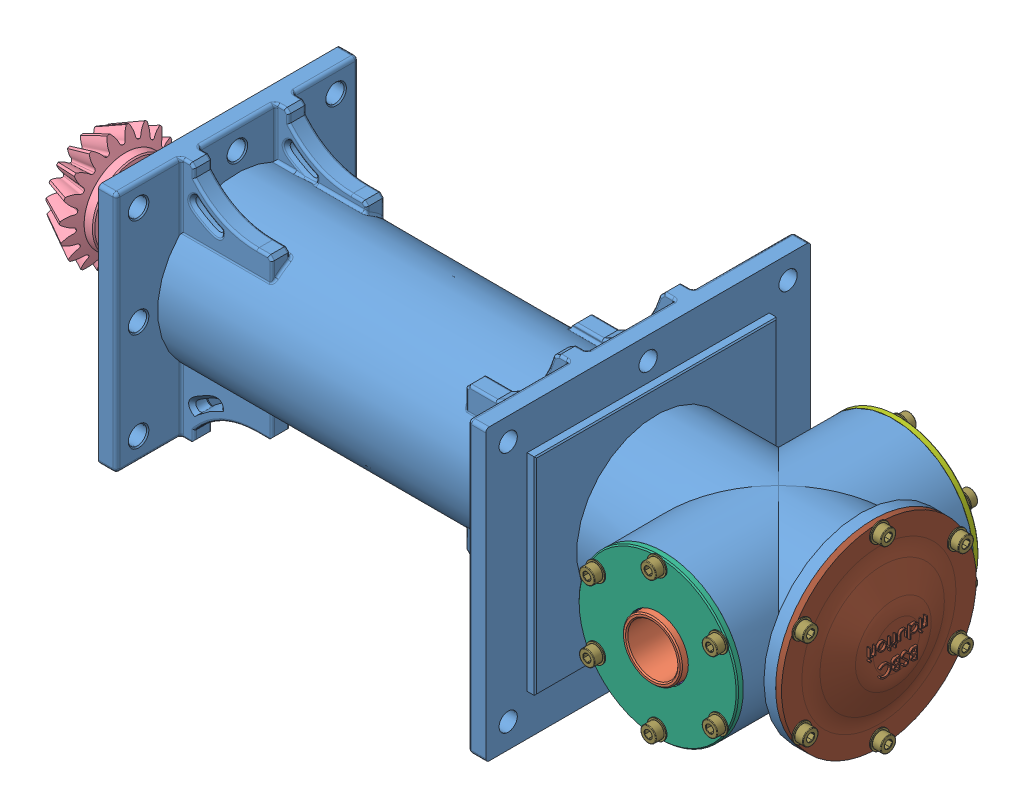
SolidWorks assembly assieme_input, configuration Default. Lengths in mm.
80 component instances, 22 part files, 63 mates.
Components (placement in the parent):
- carter input-1: carter input [Default] at (125.1796 -12.4449 563.34) size (563.34 245.5 275)
- input_ok-1: input_ok [Default] at (125.1796 -12.4449 670.74) x (0 0 1) z (0.402129 -0.915583 0) size (214.8 54.7 54.7)
- SKF_6210-1: SKF_6210 [Default] at (125.1796 -12.4449 476.84) x (0 0 1) z (0.402129 -0.915583 0) size (20 90 90)
  - SKF_6210_14-1: SKF_6210_14 [Default] x (1 0 0) z (0 -0.587785 0.809017) size (12.7 12.7 12.7)
  - SKF_6210_14-2: SKF_6210_14 [Default] x (1 0 0) z (0 -0.951057 0.309017) size (12.7 12.7 12.7)
  - SKF_6210_14-3: SKF_6210_14 [Default] x (1 0 0) z (0 -0.951057 -0.309017) size (12.7 12.7 12.7)
  - SKF_6210_14-4: SKF_6210_14 [Default] x (1 0 0) z (0 -0.587785 -0.809017) size (12.7 12.7 12.7)
  - SKF_6210_14-5: SKF_6210_14 [Default] x (1 0 0) z (0 0 -1) size (12.7 12.7 12.7)
  - SKF_6210_14-6: SKF_6210_14 [Default] x (1 0 0) z (0 0.587785 -0.809017) size (12.7 12.7 12.7)
  - SKF_6210_14-7: SKF_6210_14 [Default] x (1 0 0) z (0 0.951057 -0.309017) size (12.7 12.7 12.7)
  - SKF_6210_14-8: SKF_6210_14 [Default] x (1 0 0) z (0 0.951057 0.309017) size (12.7 12.7 12.7)
  - SKF_6210_14-9: SKF_6210_14 [Default] x (1 0 0) z (0 0.587785 0.809017) size (12.7 12.7 12.7)
  - SKF_6210_14-10: SKF_6210_14 [Default] at origin size (12.7 12.7 12.7)
  - SKF_6210_25-1: SKF_6210_25 [Default] at origin size (20 90 90)
  - SKF_6210_27-1: SKF_6210_27 [Default] at origin size (20 62.51 62.51)
- SKF_6210-2: SKF_6210 [Default] at (125.1796 -12.4449 629.84) x (0 0 1) z (0.402129 -0.915583 0) size (20 90 90)
  - SKF_6210_14-1: SKF_6210_14 [Default] x (1 0 0) z (0 -0.587785 0.809017) size (12.7 12.7 12.7)
  - SKF_6210_14-2: SKF_6210_14 [Default] x (1 0 0) z (0 -0.951057 0.309017) size (12.7 12.7 12.7)
  - SKF_6210_14-3: SKF_6210_14 [Default] x (1 0 0) z (0 -0.951057 -0.309017) size (12.7 12.7 12.7)
  - SKF_6210_14-4: SKF_6210_14 [Default] x (1 0 0) z (0 -0.587785 -0.809017) size (12.7 12.7 12.7)
  - SKF_6210_14-5: SKF_6210_14 [Default] x (1 0 0) z (0 0 -1) size (12.7 12.7 12.7)
  - SKF_6210_14-6: SKF_6210_14 [Default] x (1 0 0) z (0 0.587785 -0.809017) size (12.7 12.7 12.7)
  - SKF_6210_14-7: SKF_6210_14 [Default] x (1 0 0) z (0 0.951057 -0.309017) size (12.7 12.7 12.7)
  - SKF_6210_14-8: SKF_6210_14 [Default] x (1 0 0) z (0 0.951057 0.309017) size (12.7 12.7 12.7)
  - SKF_6210_14-9: SKF_6210_14 [Default] x (1 0 0) z (0 0.587785 0.809017) size (12.7 12.7 12.7)
  - SKF_6210_14-10: SKF_6210_14 [Default] at origin size (12.7 12.7 12.7)
  - SKF_6210_25-1: SKF_6210_25 [Default] at origin size (20 90 90)
  - SKF_6210_27-1: SKF_6210_27 [Default] at origin size (20 62.51 62.51)
- coperchio.n2-1: coperchio.n2 [Default] at (125.1796 -12.4449 665.74) x (-1 0 0) z (0 0 -1) size (135 135 15.9)
- coperchio.n3-1: coperchio.n3 [Default] at (125.1796 -12.4449 460.94) size (135 135 11)
- tenuta 0.1 e 0.2 e 6-1: tenuta 0.1 e 0.2 e 6 [Default] at (125.1796 -12.4449 463.94) x (0 0 1) z (-1 0 0) size (8 70 70)
- tenuta 0.1 e 0.2 e 6-2: tenuta 0.1 e 0.2 e 6 [Default] at (125.1796 -12.4449 662.74) x (0 0 -1) z (1 0 0) size (8 70 70)
- anello_uni_7436-55-1: anello_uni_7436-55 [Default] at (124.7248 -12.5816 584.84) x (-0.903159 -0.429307 0) z (0 0 1) size (57.38 64.07 3)
- anello_uni_7436-50-4: anello_uni_7436-50 [Default] at (124.7295 -12.5699 473.84) x (-0.915583 -0.402129 0) z (0 0 1) size (52.25 60.43 3)
- anello_uni_7436-50-6: anello_uni_7436-50 [Default] at (125.5762 -12.198 649.84) x (-0.915583 -0.402129 0) z (0 0 1) size (52.25 60.43 3)
- coperchio..n1-1: coperchio..n1 [Default] at (220.1796 -12.4449 563.34) x (1 0 0) z (0 0 -1) size (27 165 165)
- SOLID bulloni a brugola M8 coperchi vari-13: SOLID bulloni a brugola M8 coperchi vari [Default] at (125.1796 -72.4449 476.94) x (-1 0 0) z (0 0 -1) size (16 16 24.35)
- SOLID bulloni a brugola M8 coperchi vari-14: SOLID bulloni a brugola M8 coperchi vari [Default] at (73.2181 -42.4449 476.94) x (-0.5 0.866025 0) z (0 0 -1) size (16 16 24.35)
- SOLID bulloni a brugola M8 coperchi vari-15: SOLID bulloni a brugola M8 coperchi vari [Default] at (73.2181 17.5551 476.94) x (0.5 0.866025 0) z (0 0 -1) size (16 16 24.35)
- SOLID bulloni a brugola M8 coperchi vari-16: SOLID bulloni a brugola M8 coperchi vari [Default] at (125.1796 47.5551 476.94) x (1 0 0) z (0 0 -1) size (16 16 24.35)
- SOLID bulloni a brugola M8 coperchi vari-17: SOLID bulloni a brugola M8 coperchi vari [Default] at (177.1411 17.5551 476.94) x (0.5 -0.866025 0) z (0 0 -1) size (16 16 24.35)
- SOLID bulloni a brugola M8 coperchi vari-18: SOLID bulloni a brugola M8 coperchi vari [Default] at (177.1411 -42.4449 476.94) x (-0.5 -0.866025 0) z (0 0 -1) size (16 16 24.35)
- SOLID bulloni a brugola M8 coperchi vari-19: SOLID bulloni a brugola M8 coperchi vari [Default] at (125.1796 -72.4449 649.74) x (-0.820736 0.571308 0) z (0 0 1) size (16 16 24.35)
- SOLID bulloni a brugola M8 coperchi vari-20: SOLID bulloni a brugola M8 coperchi vari [Default] at (177.1411 -42.4449 649.74) x (-0.905135 -0.425124 0) z (0 0 1) size (16 16 24.35)
- SOLID bulloni a brugola M8 coperchi vari-21: SOLID bulloni a brugola M8 coperchi vari [Default] at (177.1411 17.5551 649.74) x (-0.0844 -0.996432 0) z (0 0 1) size (16 16 24.35)
- SOLID bulloni a brugola M8 coperchi vari-22: SOLID bulloni a brugola M8 coperchi vari [Default] at (125.1796 47.5551 649.74) x (0.820736 -0.571308 0) z (0 0 1) size (16 16 24.35)
- SOLID bulloni a brugola M8 coperchi vari-23: SOLID bulloni a brugola M8 coperchi vari [Default] at (73.2181 17.5551 649.74) x (0.905135 0.425124 0) z (0 0 1) size (16 16 24.35)
- SOLID bulloni a brugola M8 coperchi vari-24: SOLID bulloni a brugola M8 coperchi vari [Default] at (73.2181 -42.4449 649.74) x (0.0844 0.996432 0) z (0 0 1) size (16 16 24.35)
- SOLID bulloni a brugola M8 coperchi vari-25: SOLID bulloni a brugola M8 coperchi vari [Default] at (194.1796 -88.4449 563.34) x (0 0.000788 -1) z (1 0 0) size (16 16 24.35)
- SOLID bulloni a brugola M8 coperchi vari-26: SOLID bulloni a brugola M8 coperchi vari [Default] at (194.1796 -50.4449 629.1579) x (0 -0.865631 -0.500683) z (1 0 0) size (16 16 24.35)
- SOLID bulloni a brugola M8 coperchi vari-27: SOLID bulloni a brugola M8 coperchi vari [Default] at (194.1796 25.5551 629.1579) x (0 -0.866419 0.499317) z (1 0 0) size (16 16 24.35)
- SOLID bulloni a brugola M8 coperchi vari-28: SOLID bulloni a brugola M8 coperchi vari [Default] at (194.1796 63.5551 563.34) x (0 -0.000788 1) z (1 0 0) size (16 16 24.35)
- SOLID bulloni a brugola M8 coperchi vari-29: SOLID bulloni a brugola M8 coperchi vari [Default] at (194.1796 25.5551 497.5221) x (0 0.865631 0.500683) z (1 0 0) size (16 16 24.35)
- SOLID bulloni a brugola M8 coperchi vari-30: SOLID bulloni a brugola M8 coperchi vari [Default] at (194.1796 -50.4449 497.5221) x (0 0.866419 -0.499317) z (1 0 0) size (16 16 24.35)
- SKF_NUP_208_ECJ-2: SKF_NUP_208_ECJ [Default] at (19.4696 -12.4449 563.34) x (1 0 0) z (0 -0.998638 -0.052166) size (18 80 80)
  - SKF_NUP_208_ECJ_3-1: SKF_NUP_208_ECJ_3 [Default] x (1 0 0) z (0 -0.433884 0.900969) size (11 11 11)
  - SKF_NUP_208_ECJ_3-2: SKF_NUP_208_ECJ_3 [Default] x (1 0 0) z (0 -0.781831 0.62349) size (11 11 11)
  - SKF_NUP_208_ECJ_3-3: SKF_NUP_208_ECJ_3 [Default] x (1 0 0) z (0 -0.974928 0.222521) size (11 11 11)
  - SKF_NUP_208_ECJ_3-4: SKF_NUP_208_ECJ_3 [Default] x (1 0 0) z (0 -0.974928 -0.222521) size (11 11 11)
  - SKF_NUP_208_ECJ_3-5: SKF_NUP_208_ECJ_3 [Default] x (1 0 0) z (0 -0.781831 -0.62349) size (11 11 11)
  - SKF_NUP_208_ECJ_3-6: SKF_NUP_208_ECJ_3 [Default] x (1 0 0) z (0 -0.433884 -0.900969) size (11 11 11)
  - SKF_NUP_208_ECJ_3-7: SKF_NUP_208_ECJ_3 [Default] x (1 0 0) z (0 0 -1) size (11 11 11)
  - SKF_NUP_208_ECJ_3-8: SKF_NUP_208_ECJ_3 [Default] x (1 0 0) z (0 0.433884 -0.900969) size (11 11 11)
  - SKF_NUP_208_ECJ_3-9: SKF_NUP_208_ECJ_3 [Default] x (1 0 0) z (0 0.781831 -0.62349) size (11 11 11)
  - SKF_NUP_208_ECJ_3-10: SKF_NUP_208_ECJ_3 [Default] x (1 0 0) z (0 0.974928 -0.222521) size (11 11 11)
  - SKF_NUP_208_ECJ_3-11: SKF_NUP_208_ECJ_3 [Default] x (1 0 0) z (0 0.974928 0.222521) size (11 11 11)
  - SKF_NUP_208_ECJ_3-12: SKF_NUP_208_ECJ_3 [Default] x (1 0 0) z (0 0.781831 0.62349) size (11 11 11)
  - SKF_NUP_208_ECJ_3-13: SKF_NUP_208_ECJ_3 [Default] x (1 0 0) z (0 0.433884 0.900969) size (11 11 11)
  - SKF_NUP_208_ECJ_3-14: SKF_NUP_208_ECJ_3 [Default] at origin size (11 11 11)
  - SKF_NUP_208_ECJ_20-1: SKF_NUP_208_ECJ_20 [Default] at origin size (18 80 80)
  - SKF_NUP_208_ECJ_22-1: SKF_NUP_208_ECJ_22 [Default] at origin size (18 54 54)
- SOLID ruota 1-1: SOLID ruota 1 [Default] at (129.3382 -12.4449 563.34) x (0 -0.179924 -0.983681) z (-1 0 0) size (103.91 103.86 54.88)
- RUOTA0_OK-1: RUOTA0_OK [Default] at (125.1796 -12.4449 559.8714) x (-0.995036 -0.099517 0) z (0 0 1) size (105.59 105.67 33.5)
- anello_o40-uni_7435-4: anello_o40-uni_7435 [Default] at (86.9716 -12.4449 563.34) x (0 0.947589 0.319493) z (1 0 0) size (41.38 47.49 1.75)
- SOLID albero 2-2: SOLID albero 2 [Default] at (92.4716 -12.4449 563.34) x (0 -0.619232 -0.785208) z (-1 0 0) size (40 40 555)
- OR 1-1: OR 1 [Default] at (203.6796 -12.4449 563.34) x (0 0 -1) z (1 0 0) size (140 140 3)
- OR 2-1: OR 2 [Default] at (125.1796 -12.4449 464.44) x (0.998746 0.05006 0) z (0 0 1) size (105 105 3)
- OR 2-2: OR 2 [Default] at (125.1796 -12.4449 659.24) size (105 105 3)
- SOLID ruota 2-1: SOLID ruota 2 [Default] at (-528.6431 -12.4449 563.34) x (0 0.329379 0.944198) z (1 0 0) size (100.08 99.94 103.04)
- anello_o40-uni_7435-5: anello_o40-uni_7435 [Default] at (-456.2784 -12.4449 563.34) x (0 0.681304 -0.732001) z (1 0 0) size (41.38 47.49 1.75)
Mates (geometry in assembly coordinates):
- Concentrico2: concentric anti-aligned: cylinder of input_ok-1 through (125.1796 -12.4449 670.74) axis (0 0 -1) radius 25; cylinder of SKF_6210-1/SKF_6210_27-1 through (125.1796 -12.4449 576.84) axis (0 0 1) radius 25
- Concentrico3: concentric anti-aligned: cylinder of input_ok-1 through (125.1796 -12.4449 670.74) axis (0 0 -1) radius 25; cylinder of SKF_6210-2/SKF_6210_27-1 through (125.1796 -12.4449 729.84) axis (0 0 1) radius 25
- Coincidente1: coincident anti-aligned: plane of input_ok-1 through (100.1384 -23.4431 629.84) normal (0 0 1); plane of SKF_6210-2/SKF_6210_27-1 through (96.8987 -24.866 629.84) normal (0 0 -1)
- Coincidente2: coincident anti-aligned: plane of input_ok-1 through (102.29 -22.4981 496.84) normal (0 0 -1); plane of SKF_6210-1/SKF_6210_27-1 through (101.2829 -22.9404 496.84) normal (0 0 1)
- Concentrico6: concentric aligned: cylinder of carter input-1 through (125.1796 -12.4449 629.84) axis (0 0 1) radius 45; cylinder of SKF_6210-2/SKF_6210_25-1 through (125.1796 -12.4449 679.84) axis (0 0 1) radius 45
- Coincidente7: coincident anti-aligned: plane of carter input-1 through (125.1796 -12.4449 629.84) normal (0 0 1); plane of SKF_6210-2/SKF_6210_25-1 through (84.9855 -30.0983 629.84) normal (0 0 -1)
- Concentrico7: concentric anti-aligned: cylinder of coperchio.n2-1 through (125.1796 -12.4449 654.74) axis (0 0 1) radius 35; cylinder of tenuta 0.1 e 0.2 e 6-2 through (125.1796 -12.4449 612.74) axis (0 0 -1) radius 35
- Coincidente8: coincident anti-aligned: plane of coperchio.n2-1 through (125.1796 -12.4449 662.74) normal (0 0 -1); plane of tenuta 0.1 e 0.2 e 6-2 through (125.1796 21.5551 662.74) normal (0 0 1)
- Concentrico8: concentric aligned: cylinder of coperchio.n3-1 through (125.1796 -12.4449 463.94) axis (0 0 1) radius 35; cylinder of tenuta 0.1 e 0.2 e 6-1 through (125.1796 -12.4449 513.94) axis (0 0 1) radius 35
- Coincidente10: coincident anti-aligned: plane of coperchio.n3-1 through (125.1796 -12.4449 463.94) normal (0 0 1); plane of tenuta 0.1 e 0.2 e 6-1 through (125.1796 21.5551 463.94) normal (0 0 -1)
- Concentrico9: concentric aligned: circle of carter input-1; circle of coperchio.n3-1
- Coincidente11: coincident anti-aligned: plane of carter input-1 through (125.1796 -12.4449 465.94) normal (0 0 -1); plane of coperchio.n3-1 through (125.1796 -12.4449 465.94) normal (0 0 1)
- Concentrico10: concentric aligned: cylinder of carter input-1 through (125.1796 -12.4449 629.84) axis (0 0 1) radius 45; cylinder of coperchio.n2-1 through (125.1796 -12.4449 654.74) axis (0 0 1) radius 45
- Coincidente17: coincident anti-aligned: plane of carter input-1 through (125.1796 -12.4449 660.74) normal (0 0 1); plane of coperchio.n2-1 through (125.1796 -12.4449 660.74) normal (0 0 -1)
- Concentrico11: concentric aligned: cylinder of carter input-1 through (125.1796 -72.4449 660.74) axis (0 0 1) radius 3.4; cylinder of coperchio.n2-1 through (125.1796 -72.4449 665.74) axis (0 0 1) radius 4.5
- Concentrico14: concentric anti-aligned: cylinder of input_ok-1 through (125.1796 -12.4449 670.74) axis (0 0 -1) radius 25; cylinder of anello_uni_7436-55-1 through (125.1796 -12.4449 587.84) axis (0 0 1) radius 29.157
- Coincidente21: coincident: point of input_ok-1; line of anello_uni_7436-55-1 through (106.325 19.1391 584.84) axis (0.429307 -0.903159 0)
- Concentrico15: concentric anti-aligned: cylinder of input_ok-1 through (125.1796 -12.4449 670.74) axis (0 0 -1) radius 25; cylinder of anello_uni_7436-50-4 through (125.1796 -12.4449 476.84) axis (0 0 1) radius 26.5875
- Coincidente22: coincident anti-aligned: plane of input_ok-1 through (125.1796 -12.4449 476.84) normal (0 0 -1); plane of anello_uni_7436-50-4 through (136.1796 -4.9971 476.84) normal (0 0 1)
- Perpendicolare1: perpendicular: plane of input_ok-1 through (108.3332 -0.0751 520.94) normal (0.402129 -0.915583 0); line of anello_uni_7436-50-4 through (118.1035 9.9767 473.84) axis (-0.402129 0.915583 0)
- Concentrico17: concentric aligned: cylinder of input_ok-1 through (125.1796 -12.4449 670.74) axis (0 0 -1) radius 25; cylinder of anello_uni_7436-50-6 through (125.1796 -12.4449 649.84) axis (0 0 -1) radius 26.5875
- Perpendicolare2: perpendicular: plane of input_ok-1 through (127.4689 8.3294 583.94) normal (0.402129 -0.915583 0); plane of anello_uni_7436-50-6 through (120.2803 7.3201 651.34) normal (-0.915583 -0.402129 0)
- Coincidente26: coincident anti-aligned: plane of carter input-1 through (205.1796 -12.4449 563.34) normal (1 0 0); plane of coperchio..n1-1 through (205.1796 -69.9449 563.34) normal (-1 0 0)
- Concentrico18: concentric aligned: cylinder of carter input-1 through (205.1796 -12.4449 563.34) axis (-1 0 0) radius 82.5; cylinder of coperchio..n1-1 through (210.1796 -12.4449 563.34) axis (-1 0 0) radius 82.5
- Concentrico19: concentric anti-aligned: cone of carter input-1 through (205.1796 -88.4449 563.34) axis (-1 0 0); cylinder of coperchio..n1-1 through (210.1796 -88.4449 563.34) axis (1 0 0) radius 4.25
- Concentrico20: concentric anti-aligned: cylinder of carter input-1 through (125.1796 -72.4449 465.94) axis (0 0 -1) radius 3.4; cylinder of SOLID bulloni a brugola M8 coperchi vari-13 through (125.1796 -72.4449 460.94) axis (0 0 1) radius 4
- Vite1: screw = 1 anti-aligned: cylinder of carter input-1 through (125.1796 -72.4449 465.94) axis (0 0 -1) radius 3.4; cylinder of SOLID bulloni a brugola M8 coperchi vari-13 through (125.1796 -72.4449 460.94) axis (0 0 1) radius 4
- Coincidente27: coincident anti-aligned: plane of coperchio.n3-1 through (125.1796 -12.4449 460.94) normal (0 0 -1); plane of SOLID bulloni a brugola M8 coperchi vari-13 through (125.1796 -72.4449 460.94) normal (0 0 1)
- Coincidente28: coincident anti-aligned: plane of input_ok-1 through (125.1796 -12.4449 649.84) normal (0 0 1); plane of anello_uni_7436-50-6 through (137.0263 -4.6252 649.84) normal (0 0 -1)
- Perpendicolare3: perpendicular: plane of input_ok-1 through (127.4689 8.3294 583.94) normal (0.402129 -0.915583 0); plane of anello_uni_7436-50-6 through (120.2803 7.3201 651.34) normal (-0.915583 -0.402129 0)
- Concentrico22: concentric anti-aligned: cylinder of carter input-1 through (125.1796 -72.4449 660.74) axis (0 0 1) radius 3.4; cylinder of SOLID bulloni a brugola M8 coperchi vari-19 through (125.1796 -72.4449 665.74) axis (0 0 -1) radius 4
- Vite2: screw = 1 anti-aligned: cylinder of carter input-1 through (125.1796 -72.4449 660.74) axis (0 0 1) radius 3.4; cylinder of SOLID bulloni a brugola M8 coperchi vari-19 through (125.1796 -72.4449 665.74) axis (0 0 -1) radius 4
- Coincidente31: coincident anti-aligned: plane of coperchio.n2-1 through (125.1796 -12.4449 665.74) normal (0 0 1); plane of SOLID bulloni a brugola M8 coperchi vari-19 through (125.1796 -72.4449 665.74) normal (0 0 -1)
- Concentrico24: concentric anti-aligned: cylinder of carter input-1 through (205.1796 -88.4449 563.34) axis (1 0 0) radius 3.4; cylinder of SOLID bulloni a brugola M8 coperchi vari-25 through (210.1796 -88.4449 563.34) axis (-1 0 0) radius 4
- Vite3: screw = 1 anti-aligned: cylinder of carter input-1 through (205.1796 -88.4449 563.34) axis (1 0 0) radius 3.4; cylinder of SOLID bulloni a brugola M8 coperchi vari-25 through (210.1796 -88.4449 563.34) axis (-1 0 0) radius 4
- Coincidente32: coincident anti-aligned: plane of coperchio..n1-1 through (210.1796 -71.0431 563.34) normal (1 0 0); plane of SOLID bulloni a brugola M8 coperchi vari-25 through (210.1796 -88.4449 563.34) normal (-1 0 0)
- Coincidente42: coincident anti-aligned: plane of carter input-1 through (19.4696 -12.4449 563.34) normal (1 0 0); plane of SKF_NUP_208_ECJ-2/SKF_NUP_208_ECJ_20-1 through (19.4696 -14.4741 602.187) normal (-1 0 0)
- Coincidente52: coincident anti-aligned: plane of SKF_NUP_208_ECJ-2/SKF_NUP_208_ECJ_22-1 through (37.4696 -13.5456 584.4113) normal (1 0 0); plane of SOLID ruota 1-1 through (37.4696 -12.4449 563.34) normal (-1 0 0)
- Concentrico33: concentric anti-aligned: cylinder of input_ok-1 through (125.1796 -12.4449 670.74) axis (0 0 -1) radius 25; cylinder of RUOTA0_OK-1 through (125.1796 -12.4449 587.838) axis (0 0 1) radius 29.3436
- Coincidente53: coincident anti-aligned: plane of input_ok-1 through (125.1796 -12.4449 618.84) normal (0 0 -1); plane of RUOTA0_OK-1 through (125.1796 -12.4449 618.84) normal (0 0 1)
- Concentrico40: concentric aligned: cylinder of SOLID ruota 1-1 through (37.4696 -12.4449 563.34) axis (1 0 0) radius 25; cylinder of SOLID albero 2-2 through (-462.5284 -12.4449 563.34) axis (1 0 0) radius 20
- Concentrico41: concentric aligned: cylinder of SKF_NUP_208_ECJ-2/SKF_NUP_208_ECJ_20-1 through (33.9696 -12.4449 563.34) axis (1 0 0) radius 40; cylinder of SOLID albero 2-2 through (-462.5284 -12.4449 563.34) axis (1 0 0) radius 20
- Concentrico42: concentric anti-aligned: cylinder of anello_o40-uni_7435-4 through (86.9716 -12.4449 563.34) axis (-1 0 0) radius 18.75; cylinder of SOLID albero 2-2 through (86.9716 -12.4449 563.34) axis (1 0 0) radius 18.7
- Coincidente63: coincident anti-aligned: plane of anello_o40-uni_7435-4 through (88.7216 -22.1941 558.2337) normal (1 0 0); plane of SOLID albero 2-2 through (88.7216 -12.4449 563.34) normal (-1 0 0)
- Coincidente64: coincident anti-aligned: plane of SOLID ruota 1-1 through (86.9716 -13.9642 592.6442) normal (1 0 0); plane of anello_o40-uni_7435-4 through (86.9716 -22.1941 558.2337) normal (-1 0 0)
- Coincidente65: coincident anti-aligned: plane of SKF_NUP_208_ECJ-2/SKF_NUP_208_ECJ_22-1 through (37.4696 -13.5456 584.4113) normal (1 0 0); plane of SOLID ruota 1-1 through (37.4696 -12.4449 563.34) normal (-1 0 0)
- Concentrico43: concentric aligned: cylinder of carter input-1 through (19.4696 -12.4449 563.34) axis (1 0 0) radius 40; cylinder of SKF_NUP_208_ECJ-2/SKF_NUP_208_ECJ_20-1 through (33.9696 -12.4449 563.34) axis (1 0 0) radius 40
- Coincidente66: coincident anti-aligned: plane of carter input-1 through (19.4696 -12.4449 563.34) normal (1 0 0); plane of SKF_NUP_208_ECJ-2/SKF_NUP_208_ECJ_20-1 through (19.4696 -14.4741 602.187) normal (-1 0 0)
- AccoppiaIngranaggi1: gear = 1 : 1 mm: cone of RUOTA0_OK-1 through (125.1796 -12.4449 602.238) axis (0 0 1); cone of SOLID ruota 1-1 through (92.1725 -12.4449 563.34) axis (-1 0 0)
- Coincidente69: coincident anti-aligned: plane of SOLID ruota 1-1 through (143.4971 -1.4729 548.9196) normal (0 -0.79583 -0.60552); plane of SOLID albero 2-2 through (33.4716 -1.4729 548.9196) normal (0 0.79583 0.60552)
- Concentrico44: concentric aligned: cylinder of SKF_NUP_208_ECJ-2/SKF_NUP_208_ECJ_22-1 through (69.4696 -12.4449 563.34) axis (1 0 0) radius 20; cylinder of SOLID albero 2-2 through (-462.5284 -12.4449 563.34) axis (1 0 0) radius 20
- Coincidente70: coincident anti-aligned: plane of input_ok-1 through (117.1596 11.2338 455.94) normal (-0.947147 -0.3208 0); plane of RUOTA0_OK-1 through (117.1596 11.2338 587.838) normal (0.947147 0.3208 0)
- Concentrico45: concentric anti-aligned: cylinder of carter input-1 through (203.6796 -12.4449 563.34) axis (1 0 0) radius 70; cylinder of OR 1-1 through (206.6796 -12.4449 563.34) axis (-1 0 0) radius 70
- Coincidente71: coincident anti-aligned: plane of carter input-1 through (203.6796 -12.4449 563.34) normal (1 0 0); plane of OR 1-1 through (203.6796 -12.4449 563.34) normal (-1 0 0)
- Concentrico46: concentric aligned: cylinder of carter input-1 through (125.1796 -12.4449 467.44) axis (0 0 -1) radius 52.5; cylinder of OR 2-1 through (125.1796 -12.4449 467.44) axis (0 0 -1) radius 52.5
- Coincidente72: coincident anti-aligned: plane of carter input-1 through (125.1796 -12.4449 467.44) normal (0 0 -1); plane of OR 2-1 through (125.1796 -12.4449 467.44) normal (0 0 1)
- Concentrico47: concentric anti-aligned: cylinder of carter input-1 through (125.1796 -12.4449 659.24) axis (0 0 1) radius 52.5; cylinder of OR 2-2 through (125.1796 -12.4449 662.24) axis (0 0 -1) radius 52.5
- Coincidente74: coincident anti-aligned: plane of carter input-1 through (125.1796 -12.4449 659.24) normal (0 0 1); plane of OR 2-2 through (125.1796 -12.4449 659.24) normal (0 0 -1)
- Concentrico48: concentric anti-aligned: cylinder of SOLID albero 2-2 through (-462.5284 -12.4449 563.34) axis (1 0 0) radius 20; cylinder of SOLID ruota 2-1 through (-356.5322 -12.4449 563.34) axis (-1 0 0) radius 30
- Coincidente75: coincident anti-aligned: plane of SOLID albero 2-2 through (-352.5284 -25.9131 548.5546) normal (0 -0.739268 0.673411); plane of SOLID ruota 2-1 through (-459.3539 -24.6471 549.9445) normal (0 0.739268 -0.673411)
- Concentrico49: concentric aligned: cylinder of SOLID albero 2-2 through (-454.5284 -12.4449 563.34) axis (-1 0 0) radius 18.7; cylinder of anello_o40-uni_7435-5 through (-456.2784 -12.4449 563.34) axis (-1 0 0) radius 18.75
- Coincidente76: coincident anti-aligned: plane of SOLID albero 2-2 through (-456.2784 -12.4449 563.34) normal (1 0 0); plane of anello_o40-uni_7435-5 through (-456.2784 -21.1123 570.1222) normal (-1 0 0)
- Coincidente77: coincident anti-aligned: plane of SOLID ruota 2-1 through (-454.5284 -28.4447 542.9921) normal (-1 0 0); plane of anello_o40-uni_7435-5 through (-454.5284 -21.1123 570.1222) normal (1 0 0)
